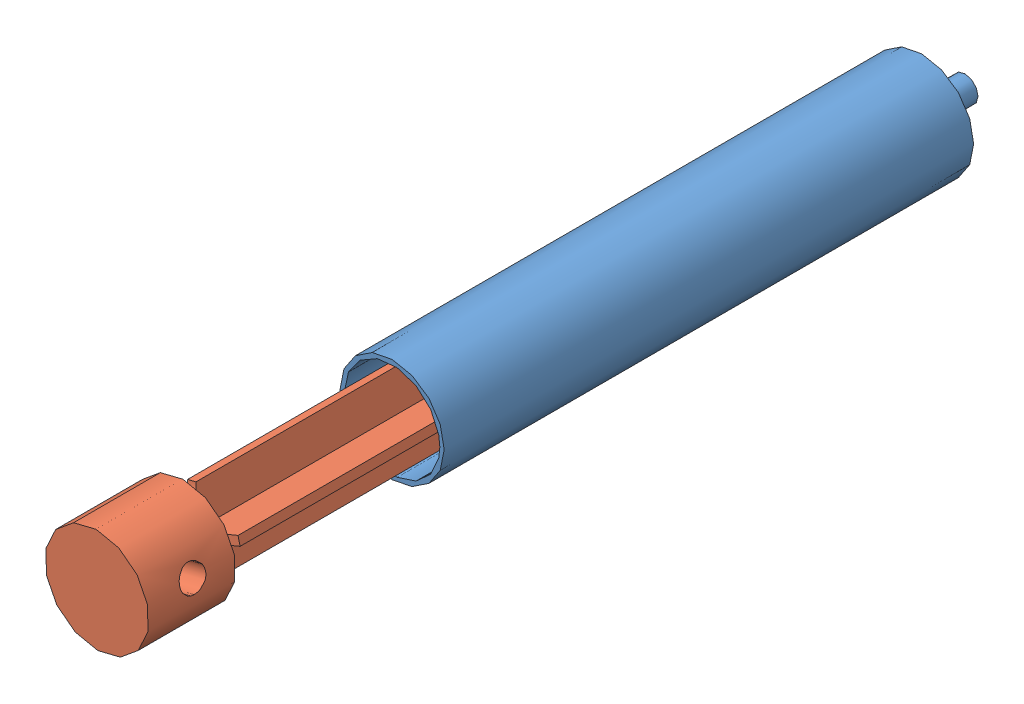
SolidWorks assembly syringe-claw, configuration Default. Lengths in mm.
Overall size (18.45 18.45 127).
2 component instances, 2 part files, 3 mates.
Components (placement in the parent):
- sr-cylinder-1: sr-cylinder [Default] at (30.2101 49.0436 27.0158) size (15.24 15.24 83.82)
- sr-plunger-1: sr-plunger [Default] at (30.2101 49.0436 47.3358) x (-0.970784 -0.239954 0) z (0 0 1) size (15.24 15.24 99.06)
Mates (geometry in assembly coordinates):
- Concentric1: concentric aligned: cylinder of sr-cylinder-1 through (30.2101 49.0436 103.2158) axis (0 0 -1) radius 6.985; cylinder of sr-plunger-1 through (30.2101 49.0436 49.8758) axis (0 0 -1) radius 6.985
- LimitDistance1: limit distance = 20.32 mm anti-aligned: plane of sr-plunger-1 through (30.2101 49.0436 47.3358) normal (0 0 -1); plane of sr-cylinder-1 through (30.2101 49.0436 27.0158) normal (0 0 1)
- Concentric2: concentric aligned: cylinder of sr-cylinder-1 through (30.2101 49.0436 103.2158) axis (0 0 -1) radius 7.62; cylinder of sr-plunger-1 through (30.2101 49.0436 146.3958) axis (0 0 -1) radius 7.62
